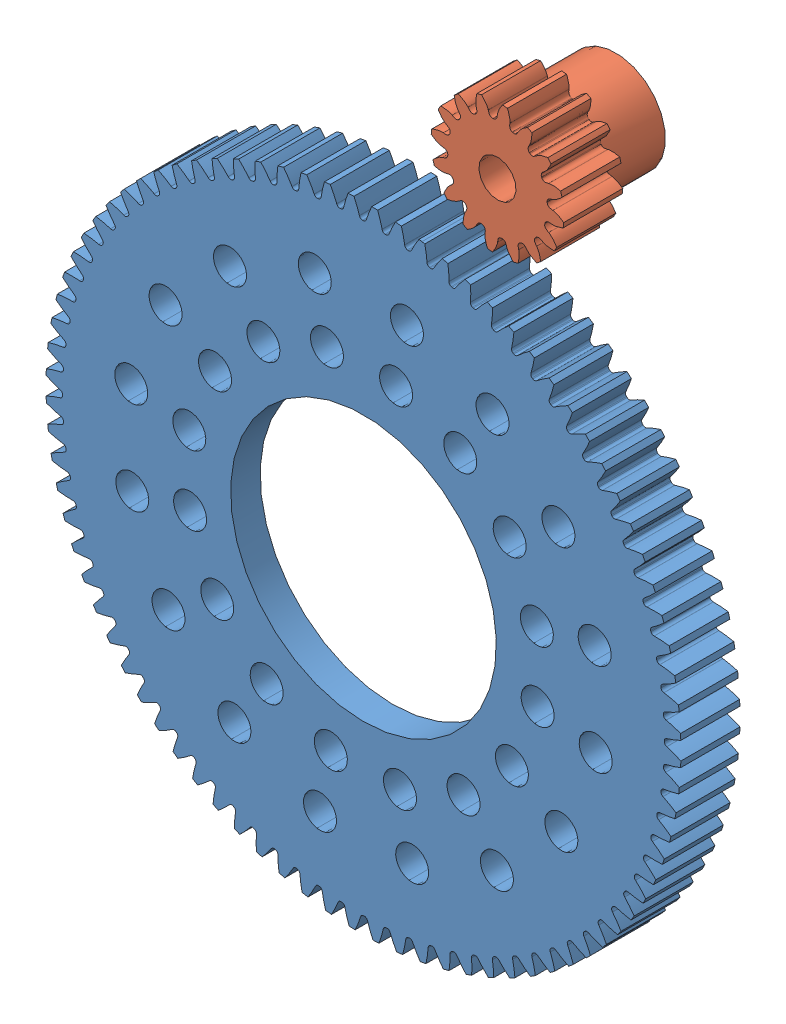
SolidWorks assembly Final L3 assembly, configuration Default. Lengths in mm.
Overall size (79.66 93.36 85.02).
20 component instances, 13 part files, 48 mates.
Components (placement in the parent):
- L3v1 Base-1: L3v1 Base [Default] at (8.4803 58.2755 10.2579) x (1 0 0) z (0 -1 0) size (38.1 152.4 47.24) (hidden)
- J2v2 Angle Bracket 585508-2: J2v2 Angle Bracket 585508 [Default] at (-8.1567 59.6725 10.2579) x (0 1 0) z (-1 0 0) size (33.02 12.43 7.88) (hidden)
- 12 wire slip ring-1: 12 wire slip ring [Default] at (8.4803 56.4975 -1.6671) x (0.999999 -0.001711 0) z (-0.001711 -0.999999 0) size (44 39.4 44) (hidden)
- L3v1 SlipRingBlock-2: L3v1 SlipRingBlock [Default] at (8.4803 56.4975 7.0829) x (-1 0 0) z (0 -1 0) size (41.15 6.35 44.45) (hidden)
- 0.5 oilite bushing-1: 0.5 oilite bushing [6338K572] at (8.4803 58.2755 69.6304) x (1 0 0) z (0 -1 0) size (22.23 12.7 22.23) (hidden)
- J2v2 Angle Bracket 585508-3: J2v2 Angle Bracket 585508 [Default] at (25.1173 58.2755 77.5679) x (0 -1 0) z (1 0 0) size (33.02 12.43 7.88) (hidden)
- J2v2 Angle Bracket 585508-4: J2v2 Angle Bracket 585508 [Default] at (-8.1567 58.2755 77.5679) x (0 1 0) z (-1 0 0) size (33.02 12.43 7.88) (hidden)
- L3v1 Bushing Support-1: L3v1 Bushing Support [Default] at (8.4803 58.2755 71.2179) x (1 0 0) z (0 -1 0) size (41.15 3.17 33.02) (hidden)
- J2v2 Angle Bracket 585508-1: J2v2 Angle Bracket 585508 [Default] at (25.1173 59.6725 10.2579) x (0 -1 0) z (1 0 0) size (33.02 12.43 7.88) (hidden)
- Link3 to 4 Shaft-1: Link3 to 4 Shaft [Default] at (8.4803 58.2755 120.6844) x (0 0 -1) z (0.883354 -0.468706 0) size (105.92 12.45 12.45) (hidden)
- L3v1 Spacer-1: L3v1 Spacer [Default] at (43.5069 58.2755 111.8579) x (0 1 0) z (0 0 1) size (35.56 15.98 35.56) (hidden)
- 0.5 oilite bushing-2: 0.5 oilite bushing [6338K572] at (8.4803 58.2755 170.7148) x (1 0 0) z (0 1 0) size (22.23 12.7 22.23) (hidden)
- 84T 32DP 1in bore plate gear-1: 84T 32DP 1in bore plate gear [Default] at (8.4803 58.2755 171.6622) x (-0.184059 -0.982915 0) z (0 0 -1) size (68.26 68.26 6.35)
- 56 rpm motor-1: 56 rpm motor [Default] at (8.4804 100.9475 141.4877) x (0 0 1) z (-1 0 0) size (74.8 24.8 24.8) (hidden)
- L3v1 Bushing Support-2: L3v1 Bushing Support [Default] at (8.4803 58.2755 169.1273) x (1 0 0) z (0 1 0) size (41.15 3.17 33.02) (hidden)
- J2v2 Angle Bracket 585508-9: J2v2 Angle Bracket 585508 [Default] at (-8.1567 58.2755 162.6579) x (0 -1 0) z (-1 0 0) size (33.02 12.43 7.88) (hidden)
- J2v2 Angle Bracket 585508-10: J2v2 Angle Bracket 585508 [Default] at (25.1173 58.2755 162.6579) x (0 1 0) z (1 0 0) size (33.02 12.43 7.88) (hidden)
- .5ID 1.125OD Flange Bearing-1: .5ID 1.125OD Flange Bearing [Default] at (8.4803 58.2755 165.7059) x (-0.115864 -0.993265 0) z (-0.993265 0.115864 0) size (31.17 7.94 31.17) (hidden)
- 4mm 16 tooth pinion gear-1: 4mm 16 tooth pinion gear [Default] at (20.2472 134.6758 166.5432) x (-0.622481 0.782635 0) z (0 0 1) size (14.29 14.29 12.7)
- motor mount bracket-1: motor mount bracket [Default] at (-10.5697 81.8975 141.4877) size (38.1 25.4 28.57) (hidden)
Mates (geometry in assembly coordinates):
- Coincident5: coincident anti-aligned: plane of L3v1 Base-1 through (8.4803 58.2755 10.2579) normal (0 0 -1); plane of J2v2 Angle Bracket 585508-1 through (25.1173 59.6725 10.2579) normal (0 0 1)
- Coincident7: coincident anti-aligned: plane of L3v1 Base-1 through (24.3553 37.8285 162.6579) normal (-1 0 0); plane of J2v2 Angle Bracket 585508-1 through (24.3553 49.2433 19.5136) normal (1 0 0)
- Coincident8: coincident anti-aligned: plane of L3v1 Base-1 through (-7.3947 37.8285 162.6579) normal (1 0 0); plane of J2v2 Angle Bracket 585508-2 through (-7.3947 70.1018 19.5136) normal (-1 0 0)
- Coincident9: coincident anti-aligned: plane of L3v1 Base-1 through (8.4803 58.2755 10.2579) normal (0 0 -1); plane of J2v2 Angle Bracket 585508-2 through (-8.1567 59.6725 10.2579) normal (0 0 1)
- Coincident10: coincident aligned: plane of J2v2 Angle Bracket 585508-1 through (29.0543 76.1825 7.0829) normal (0 1 0); plane of J2v2 Angle Bracket 585508-2 through (-12.0937 76.1825 7.0829) normal (0 1 0)
- Distance2: distance = 5.715 mm aligned: plane of J2v2 Angle Bracket 585508-1 through (29.0543 76.1825 7.0829) normal (0 1 0); plane of L3v1 Base-1 through (-10.5697 81.8975 162.6579) normal (0 1 0)
- Coincident16: coincident anti-aligned: plane of J2v2 Angle Bracket 585508-1 through (25.1173 59.6725 7.0829) normal (0 0 -1); plane of L3v1 SlipRingBlock-2 through (8.4803 56.4975 7.0829) normal (0 0 1)
- Concentric4: concentric anti-aligned: circle of J2v2 Angle Bracket 585508-1; cylinder of L3v1 SlipRingBlock-2 through (25.8793 73.1429 0.7329) axis (0 0 -1) radius 1.8986
- Concentric5: concentric anti-aligned: circle of J2v2 Angle Bracket 585508-2; circle of L3v1 SlipRingBlock-2
- Coincident17: coincident anti-aligned: plane of 12 wire slip ring-1 through (8.4803 56.4975 0.7329) normal (0 0 1); plane of L3v1 SlipRingBlock-2 through (8.4803 56.4975 0.7329) normal (0 0 -1)
- Concentric6: concentric anti-aligned: cylinder of 12 wire slip ring-1 through (8.4803 56.4975 -29.6671) axis (0 0 1) radius 11; cylinder of L3v1 SlipRingBlock-2 through (8.4803 56.4975 7.0829) axis (0 0 -1) radius 11.43
- Coincident22: coincident anti-aligned: plane of L3v1 Base-1 through (-7.3947 37.8285 162.6579) normal (1 0 0); plane of J2v2 Angle Bracket 585508-4 through (-7.3947 68.7048 86.8236) normal (-1 0 0)
- Coincident23: coincident anti-aligned: plane of L3v1 Base-1 through (-7.3947 42.591 77.5679) normal (0 0 -1); plane of J2v2 Angle Bracket 585508-4 through (-8.1567 58.2755 77.5679) normal (0 0 1)
- Width2: width aligned: plane of J2v2 Angle Bracket 585508-4 through (-12.0937 74.7855 74.3929) normal (0 1 0); plane of L3v1 Base-1 through (-12.0937 41.7655 74.3929) normal (0 -1 0); plane of J2v2 Angle Bracket 585508-4 through (-10.5697 81.8975 162.6579) normal (0 1 0); plane of L3v1 Base-1 through (-10.5697 34.6535 162.6579) normal (0 -1 0)
- Coincident24: coincident anti-aligned: plane of L3v1 Base-1 through (24.3553 37.8285 162.6579) normal (-1 0 0); plane of J2v2 Angle Bracket 585508-3 through (24.3553 68.7048 86.8236) normal (1 0 0)
- Coincident25: coincident aligned: plane of J2v2 Angle Bracket 585508-3 through (25.1173 58.2755 74.3929) normal (0 0 -1); plane of J2v2 Angle Bracket 585508-4 through (-8.1567 58.2755 74.3929) normal (0 0 -1)
- Coincident26: coincident aligned: plane of J2v2 Angle Bracket 585508-3 through (29.0543 74.7855 74.3929) normal (0 1 0); plane of J2v2 Angle Bracket 585508-4 through (-12.0937 74.7855 74.3929) normal (0 1 0)
- Coincident27: coincident anti-aligned: plane of J2v2 Angle Bracket 585508-4 through (-8.1567 58.2755 74.3929) normal (0 0 -1); plane of L3v1 Bushing Support-1 through (26.5143 72.2455 74.3929) normal (0 0 1)
- Width3: width anti-aligned: plane of L3v1 Bushing Support-1 through (26.5143 74.7855 74.3929) normal (0 1 0); plane of J2v2 Angle Bracket 585508-4 through (26.5143 41.7655 74.3929) normal (0 -1 0); plane of L3v1 Bushing Support-1 through (-12.0937 41.7655 74.3929) normal (0 -1 0); plane of J2v2 Angle Bracket 585508-4 through (-12.0937 74.7855 74.3929) normal (0 1 0)
- Coincident28: coincident aligned: plane of J2v2 Angle Bracket 585508-4 through (-12.0937 41.7655 74.3929) normal (-1 0 0); plane of L3v1 Bushing Support-1 through (-12.0937 44.3055 74.3929) normal (-1 0 0)
- Coincident29: coincident anti-aligned: plane of 0.5 oilite bushing-1 through (8.4803 58.2755 71.2179) normal (0 0 1); plane of L3v1 Bushing Support-1 through (26.5143 72.2455 71.2179) normal (0 0 -1)
- Concentric7: concentric anti-aligned: cylinder of 0.5 oilite bushing-1 through (8.4803 58.2755 82.3304) axis (0 0 -1) radius 6.3627; cylinder of L3v1 Bushing Support-1 through (8.4803 58.2755 71.2179) axis (0 0 1) radius 7.9502
- Concentric8: concentric anti-aligned: cylinder of 0.5 oilite bushing-1 through (8.4803 58.2755 82.3304) axis (0 0 -1) radius 6.3627; cylinder of Link3 to 4 Shaft-1 through (8.4803 58.2755 67.7254) axis (0 0 1) radius 6.223
- Coincident30: coincident aligned: plane of 0.5 oilite bushing-1 through (8.4803 58.2755 69.6304) normal (0 0 -1); plane of Link3 to 4 Shaft-1 through (8.4803 58.2755 69.6304) normal (0 0 -1)
- Coincident31: coincident anti-aligned: plane of L3v1 Base-1 through (27.5303 34.6535 162.6579) normal (1 0 0); plane of L3v1 Spacer-1 through (27.5303 58.2755 111.8579) normal (-1 0 0)
- Concentric9: concentric anti-aligned: cylinder of L3v1 Base-1 through (27.5303 58.2755 111.8579) axis (-1 0 0) radius 9.525; cylinder of L3v1 Spacer-1 through (27.5303 58.2755 111.8579) axis (1 0 0) radius 9.525
- Concentric10: concentric anti-aligned: cylinder of L3v1 Base-1 through (27.5303 48.3973 121.7362) axis (-1 0 0) radius 2.5527; cylinder of L3v1 Spacer-1 through (27.5303 48.3973 121.7362) axis (1 0 0) radius 2.5527
- Concentric15: concentric anti-aligned: cylinder of Link3 to 4 Shaft-1 through (8.4803 58.2755 67.7254) axis (0 0 1) radius 6.223; cylinder of 84T 32DP 1in bore plate gear-1 through (8.4803 58.2755 171.6622) axis (0 0 -1) radius 14.2875
- Concentric18: concentric aligned: cylinder of Link3 to 4 Shaft-1 through (8.4803 58.2755 67.7254) axis (0 0 1) radius 6.223; cylinder of 0.5 oilite bushing-2 through (8.4803 58.2755 158.0148) axis (0 0 1) radius 6.3627
- Concentric22: concentric anti-aligned: cylinder of Link3 to 4 Shaft-1 through (8.4803 58.2755 67.7254) axis (0 0 1) radius 6.223; cylinder of 84T 32DP 1in bore plate gear-1 through (8.4803 58.2755 171.6622) axis (0 0 -1) radius 14.2875
- Concentric25: concentric anti-aligned: cylinder of 0.5 oilite bushing-2 through (8.4803 58.2755 158.0148) axis (0 0 1) radius 7.9502; cylinder of L3v1 Bushing Support-2 through (8.4803 58.2755 169.1273) axis (0 0 -1) radius 7.9502
- Parallel5: parallel aligned: plane of 12 wire slip ring-1 through (8.4803 56.4975 -29.6671) normal (0 0 -1); plane of 56 rpm motor-1 through (8.4804 100.9475 84.4877) normal (0 0 -1)
- Symmetric6: symmetric aligned: plane of L3v1 Base-1 through (27.5303 34.6535 162.6579) normal (1 0 0); plane of L3v1 Base-1 through (-10.5697 34.6535 162.6579) normal (-1 0 0); plane of 56 rpm motor-1 through (8.4804 100.9475 141.4877) normal (-1 0 0)
- Coincident68: coincident anti-aligned: plane of L3v1 Base-1 through (-7.3947 37.8285 162.6579) normal (1 0 0); plane of J2v2 Angle Bracket 585508-9 through (-7.3947 68.7048 153.4021) normal (-1 0 0)
- Coincident69: coincident aligned: plane of L3v1 Bushing Support-2 through (26.5143 74.7855 165.9523) normal (0 1 0); plane of J2v2 Angle Bracket 585508-9 through (-12.0937 74.7855 165.8329) normal (0 1 0)
- Coincident70: coincident anti-aligned: plane of L3v1 Base-1 through (8.4803 58.2755 162.6579) normal (0 0 1); plane of J2v2 Angle Bracket 585508-9 through (-8.1567 58.2755 162.6579) normal (0 0 -1)
- Coincident71: coincident anti-aligned: plane of L3v1 Base-1 through (24.3553 37.8285 162.6579) normal (-1 0 0); plane of J2v2 Angle Bracket 585508-10 through (24.3553 68.7048 153.4021) normal (1 0 0)
- Coincident72: coincident aligned: plane of L3v1 Bushing Support-2 through (26.5143 74.7855 165.9523) normal (0 1 0); plane of J2v2 Angle Bracket 585508-10 through (29.0543 74.7855 165.8329) normal (0 1 0)
- Coincident73: coincident anti-aligned: plane of L3v1 Base-1 through (8.4803 58.2755 162.6579) normal (0 0 1); plane of J2v2 Angle Bracket 585508-10 through (25.1173 58.2755 162.6579) normal (0 0 -1)
- Concentric31: concentric aligned: cylinder of 84T 32DP 1in bore plate gear-1 through (8.4803 58.2755 171.6622) axis (0 0 -1) radius 14.2875; cylinder of .5ID 1.125OD Flange Bearing-1 through (8.4803 58.2755 171.6622) axis (0 0 -1) radius 14.2875
- Coincident80: coincident anti-aligned: plane of 84T 32DP 1in bore plate gear-1 through (-24.5939 64.9528 171.6622) normal (0 0 1); plane of .5ID 1.125OD Flange Bearing-1 through (8.4803 58.2755 171.6622) normal (0 0 -1)
- Coincident86: coincident aligned: plane of Link3 to 4 Shaft-1 through (8.4803 58.2755 173.6434) normal (0 0 1); plane of .5ID 1.125OD Flange Bearing-1 through (8.4803 58.2755 173.6434) normal (0 0 1)
- Coincident87: coincident anti-aligned: plane of L3v1 Base-1 through (-10.5697 81.8975 162.6579) normal (0 1 0); plane of motor mount bracket-1 through (-10.5697 81.8975 141.4877) normal (0 -1 0)
- Coincident88: coincident aligned: plane of L3v1 Base-1 through (27.5303 34.6535 162.6579) normal (1 0 0); plane of motor mount bracket-1 through (27.5303 85.0725 141.4877) normal (1 0 0)
- Coincident92: coincident aligned: plane of 84T 32DP 1in bore plate gear-1 through (-24.5939 64.9528 171.6622) normal (0 0 1); plane of 4mm 16 tooth pinion gear-1 through (17.8687 97.1909 171.6622) normal (0 0 1)
- Concentric32: concentric anti-aligned: circle of 56 rpm motor-1; circle of motor mount bracket-1
- Coincident93: coincident anti-aligned: plane of 56 rpm motor-1 through (8.4804 100.9475 141.4877) normal (0 0 1); plane of motor mount bracket-1 through (-10.5697 81.8975 141.4877) normal (0 0 -1)
- GearMate1: gear = 28.575 : 4 mm: cylinder of 4mm 16 tooth pinion gear-1 through (22.8866 101.7668 158.9622) axis (0 0 1) radius 2; cylinder of 84T 32DP 1in bore plate gear-1 through (8.4803 58.2755 171.6622) axis (0 0 -1) radius 14.2875
